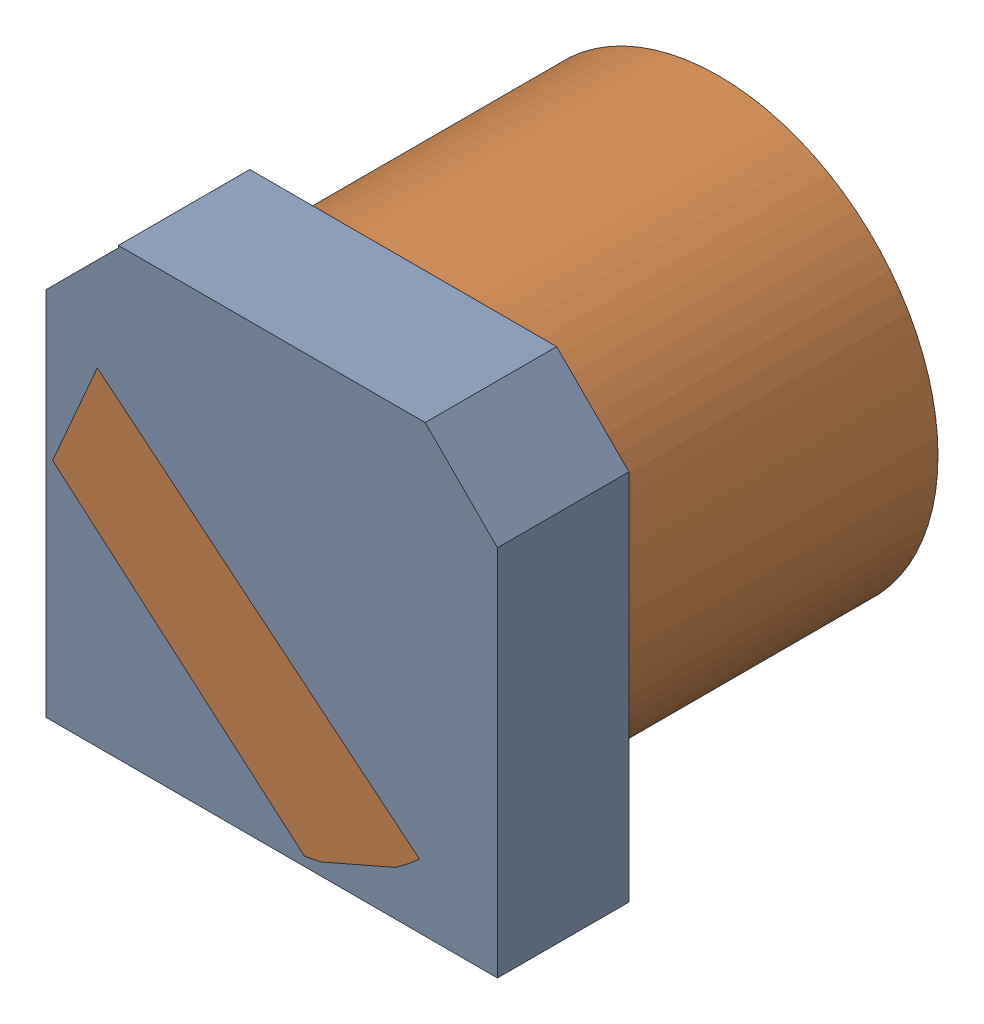
SolidWorks assembly C12, configuration Default. Lengths in mm.
Overall size (10.3 10.15 10.2).
4 component instances, 2 part files, 0 mates.
Components (placement in the parent):
- 402660496-1: 402660496 [Default] at (24.5618 65.8634 -4.1024) size (10.3 10.15 3)
  - Extruded_10-1: Extruded_10 [Default] at origin size (10.3 10.15 3)
- 405594336-1: 405594336 [Default] at (24.5619 65.9383 -1.1024) x (1 0 0) z (0 0 -1) size (10 10 10.2)
  - Cylinder-1: Cylinder [Default] at origin size (10 10 10.2)
